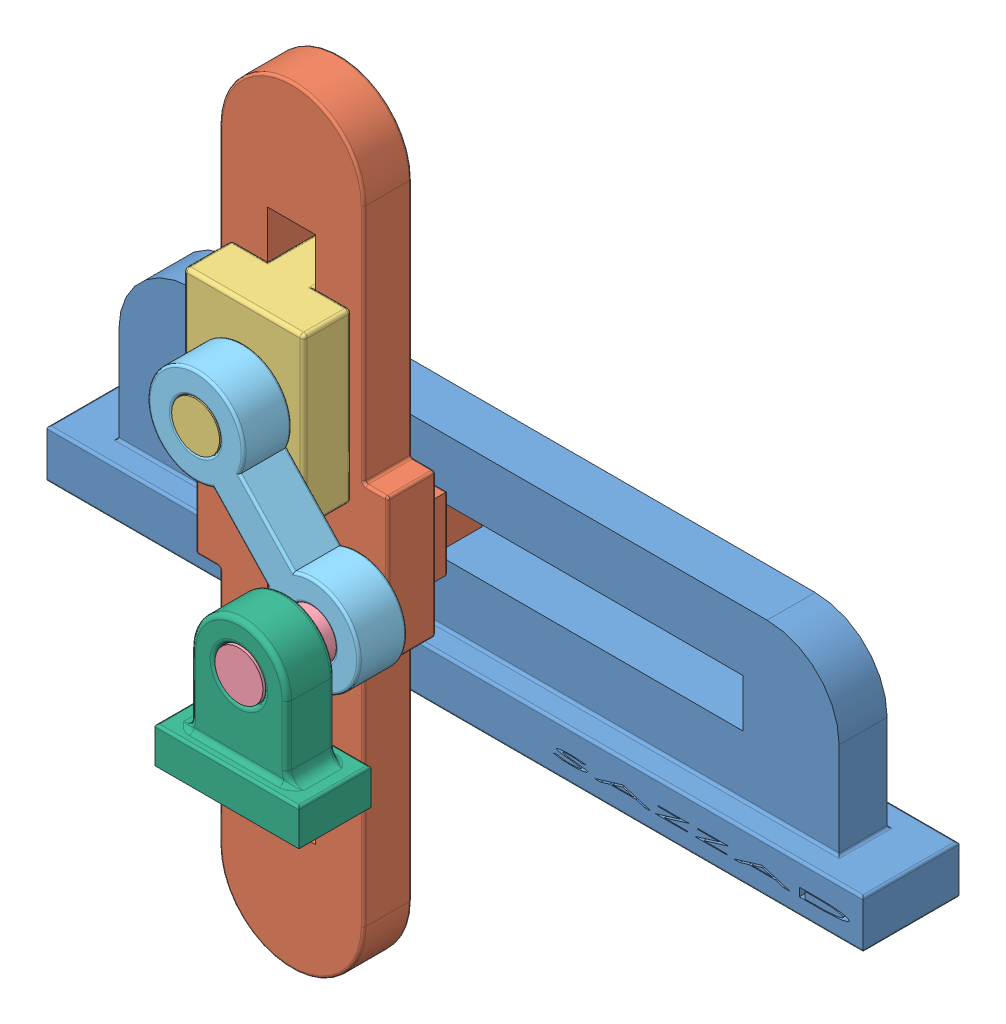
SolidWorks assembly E3_S4_AVA_E, configuration Default. Lengths in mm.
Overall size (340 320 135).
6 component instances, 6 part files, 13 mates.
Components (placement in the parent):
- E3_S4_AVA_P1-1: E3_S4_AVA_P1 [Default] at (147.8453 187.0403 240.1985) size (340 90 40)
- E3_S4_AVA_P2-1: E3_S4_AVA_P2 [Default] at (99.8074 317.0403 290.1985) x (-1 0 0) z (0 0 -1) size (80 320 50)
- E3_S4_AVA_P3-1: E3_S4_AVA_P3 [Default] at (74.8074 242.9555 310.1985) size (50 70 60)
- E3_S4_AVA_P4-1: E3_S4_AVA_P4 [Default] at (147.8453 192.0403 310.1985) x (0.949485 -0.313812 0) z (0 0 1) size (20 20 50)
- E3_S4_AVA_P5-1: E3_S4_AVA_P5 [Default] at (147.8453 192.0403 310.1985) x (-0.72736 -0.686256 0) z (0 0 1) size (40 110 20)
- E3_S4_AVA_P6-1: E3_S4_AVA_P6 [Default] at (117.8453 162.0403 365.1985) x (1 0 0) z (0 -1 0) size (60 30 65)
Mates (geometry in assembly coordinates):
- Coincident3: coincident anti-aligned: plane of E3_S4_AVA_P1-1 through (37.8453 197.0403 260.1985) normal (0 -1 0); plane of E3_S4_AVA_P2-1 through (129.8074 197.0403 240.1985) normal (0 1 0)
- Coincident4: coincident anti-aligned: plane of E3_S4_AVA_P1-1 through (-22.1547 132.0403 270.1985) normal (0 0 1); plane of E3_S4_AVA_P2-1 through (99.8074 317.0403 270.1985) normal (0 0 -1)
- Coincident5: coincident anti-aligned: plane of E3_S4_AVA_P2-1 through (109.8074 77.0403 270.1985) normal (-1 0 0); plane of E3_S4_AVA_P3-1 through (109.8074 277.9555 290.1985) normal (1 0 0)
- Coincident6: coincident anti-aligned: plane of E3_S4_AVA_P2-1 through (99.8074 317.0403 290.1985) normal (0 0 1); plane of E3_S4_AVA_P3-1 through (124.8074 277.9555 290.1985) normal (0 0 -1)
- Concentric1: concentric aligned: cylinder of E3_S4_AVA_P3-1 through (99.8074 242.9555 330.1985) axis (0 0 -1) radius 10; cylinder of E3_S4_AVA_P5-1 through (99.8074 242.9555 330.1985) axis (0 0 -1) radius 10
- Coincident7: coincident aligned: plane of E3_S4_AVA_P3-1 through (99.8074 242.9555 330.1985) normal (0 0 1); plane of E3_S4_AVA_P5-1 through (147.8453 192.0403 330.1985) normal (0 0 1)
- Concentric2: concentric aligned: cylinder of E3_S4_AVA_P4-1 through (147.8453 192.0403 360.1985) axis (0 0 -1) radius 10; cylinder of E3_S4_AVA_P5-1 through (147.8453 192.0403 330.1985) axis (0 0 -1) radius 10
- Coincident8: coincident aligned: plane of E3_S4_AVA_P4-1 through (147.8453 192.0403 310.1985) normal (0 0 -1); plane of E3_S4_AVA_P5-1 through (147.8453 192.0403 310.1985) normal (0 0 -1)
- Coincident9: coincident anti-aligned: plane of E3_S4_AVA_P1-1 through (147.8453 147.0403 240.1985) normal (0 1 0); plane of E3_S4_AVA_P6-1 through (117.8453 147.0403 365.1985) normal (0 -1 0)
- Coincident11: coincident: line of E3_S4_AVA_P1-1 through (147.8453 147.0403 270.1985) axis (0 0 -1); plane of E3_S4_AVA_P6-1 through (117.8453 147.0403 365.1985) normal (0 -1 0)
- Coincident12: coincident anti-aligned: line of E3_S4_AVA_P1-1 through (147.8453 147.0403 270.1985) axis (0 0 -1); line of E3_S4_AVA_P6-1 through (147.8453 147.0403 335.1985) axis (0 0 1)
- Concentric3: concentric aligned: cylinder of E3_S4_AVA_P4-1 through (147.8453 192.0403 360.1985) axis (0 0 -1) radius 10; cylinder of E3_S4_AVA_P6-1 through (147.8453 192.0403 360.1985) axis (0 0 -1) radius 10
- Coincident13: coincident aligned: plane of E3_S4_AVA_P4-1 through (147.8453 192.0403 360.1985) normal (0 0 1); plane of E3_S4_AVA_P6-1 through (147.8453 192.0403 360.1985) normal (0 0 1)
